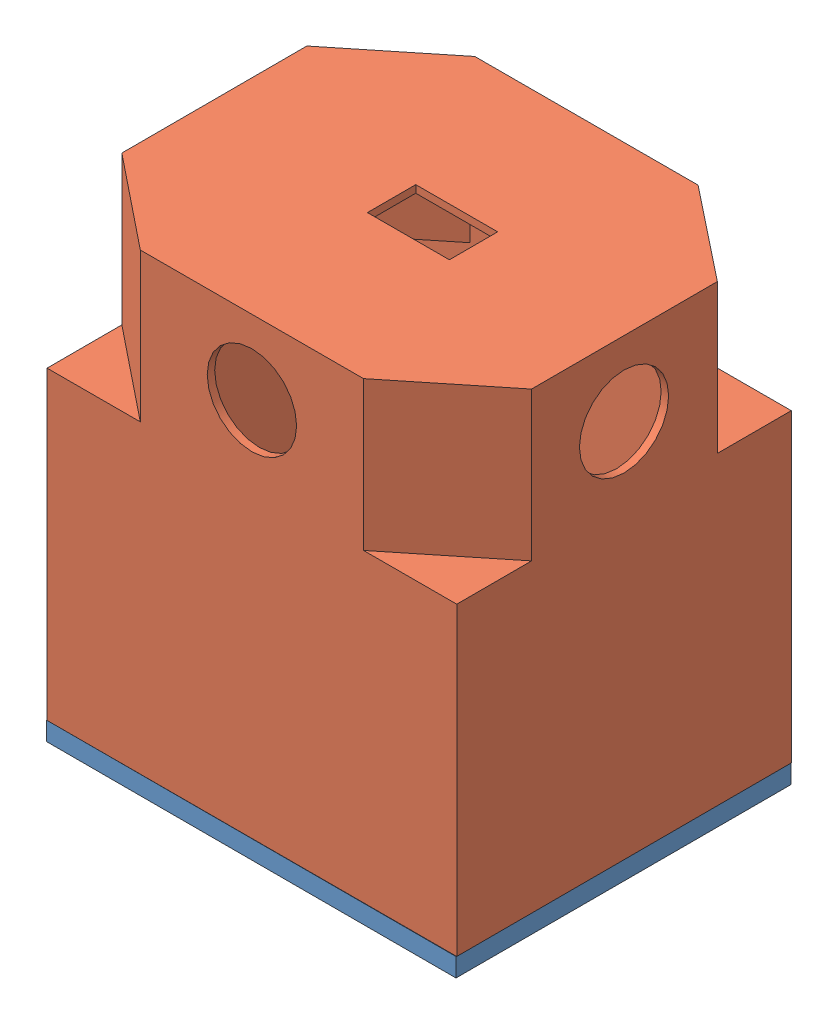
SolidWorks assembly Assem1, configuration Default. Lengths in mm.
Overall size (110.09 127 90.11).
2 component instances, 2 part files, 2 mates.
Components (placement in the parent):
- BOTTOM_Part-1: BOTTOM_Part [Default] at origin size (110 25 90)
- TOP_PART-2: TOP_PART [Default] at (-3.2716 87 -14.6123) x (-0.001041 0 -0.999999) z (-0.999999 0 0.001041) size (90 122 110)
Mates (geometry in assembly coordinates):
- Coincident3: coincident anti-aligned: plane of BOTTOM_Part-1 through (0 5 0) normal (0 1 0); plane of TOP_PART-2 through (0.7007 5 95.5126) normal (0 -1 0)
- Coincident5: coincident: point of BOTTOM_Part-1; line of TOP_PART-2 through (-55 5 -45) axis (0 1 0)
